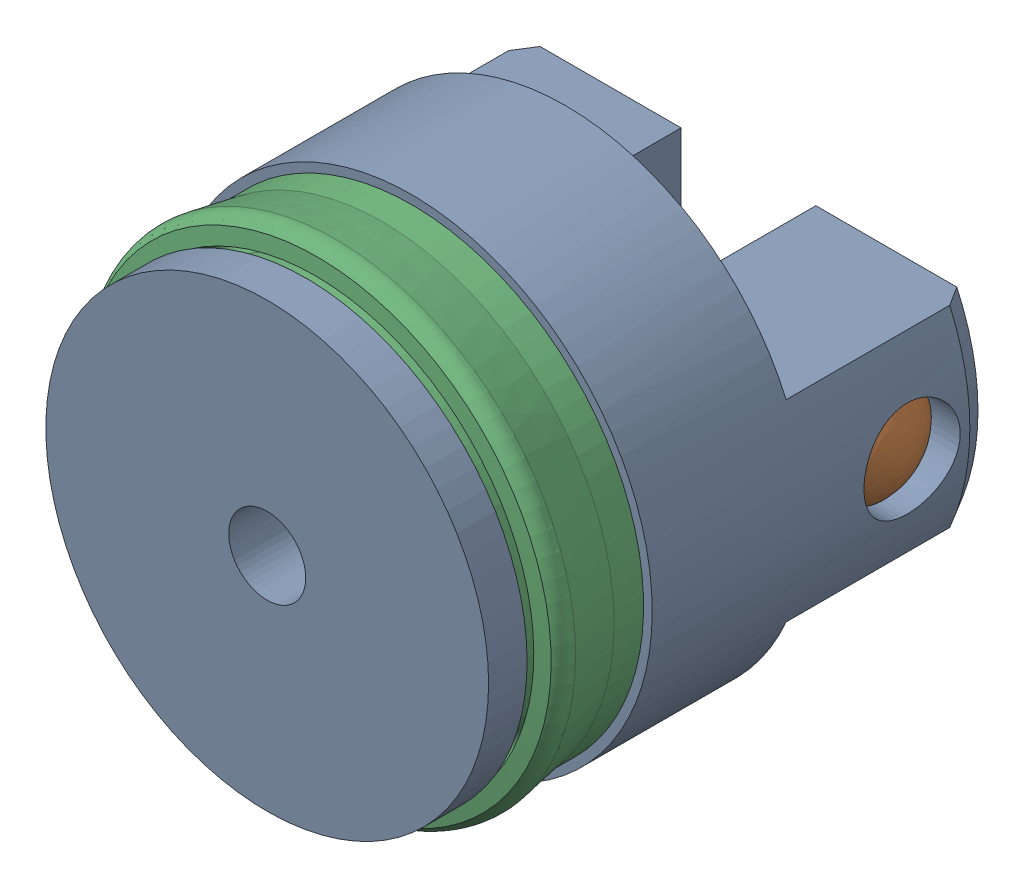
SolidWorks assembly CE_Piston, configuration Défaut. Lengths in mm.
Overall size (32.65 32.65 25).
3 component instances, 3 part files, 4 mates.
Components (placement in the parent):
- Piston-1: Piston [Défaut] at origin size (25 25 25)
- Axe de 5-1: Axe de 5 [Défaut] x (0 0 -1) z (0 1 0) size (5 24.1 5)
- Joint en U 25x17x5,5-1: Joint en U 25x17x5,5 [Défaut] at (0 0 19) x (0 0 -1) z (0.381849 0.924225 0) size (5.5 25 25)
Mates (geometry in assembly coordinates):
- Concentrique1: concentric aligned: cylinder of Piston-1 through (0 0 13.5) axis (0 0 1) radius 8.5; cylinder of Joint en U 25x17x5,5-1 through (0 0 24) axis (0 0 1) radius 8.35
- Coïncidente1: coincident anti-aligned: plane of Piston-1 through (0 0 13.5) normal (0 0 1); plane of Joint en U 25x17x5,5-1 through (-7.7173 3.1884 13.5) normal (0 0 -1)
- Concentrique2: concentric anti-aligned: cylinder of Piston-1 through (-12.5 0 0) axis (1 0 0) radius 2.5; cylinder of Axe de 5-1 through (-11.9802 0 0) axis (-1 0 0) radius 2.5
- Coïncidente2: coincident: point of Piston-1; point of Axe de 5-1
